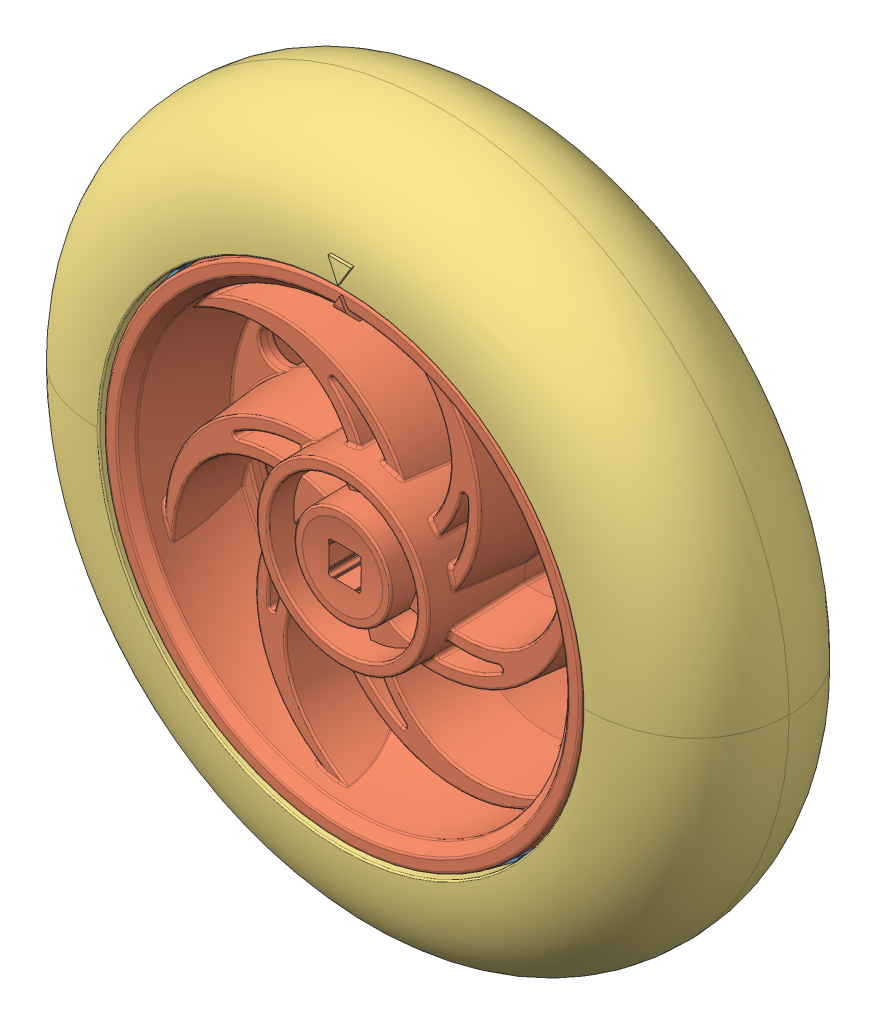
SolidWorks assembly VEX-SMALL-WHEEL, configuration Default. Lengths in mm.
Overall size (69.86 69.86 20.66).
3 component instances, 3 part files, 0 mates.
Components (placement in the parent):
- SMALL-WHEEL-RIM-1: SMALL-WHEEL-RIM [Default] at (-15.1515 15.6838 -2.6601) size (61.43 61.43 9.24)
- SMALL-WHEEL-HUB-1: SMALL-WHEEL-HUB [Default] at (-15.1515 15.6838 -2.6601) size (61.36 61.43 20.66)
- SMALL-WHEEL-TIRE-1: SMALL-WHEEL-TIRE [Default] at (-15.1515 15.6838 -2.6601) x (1 0 0) z (0 -1 0) size (69.86 19.99 69.86)
